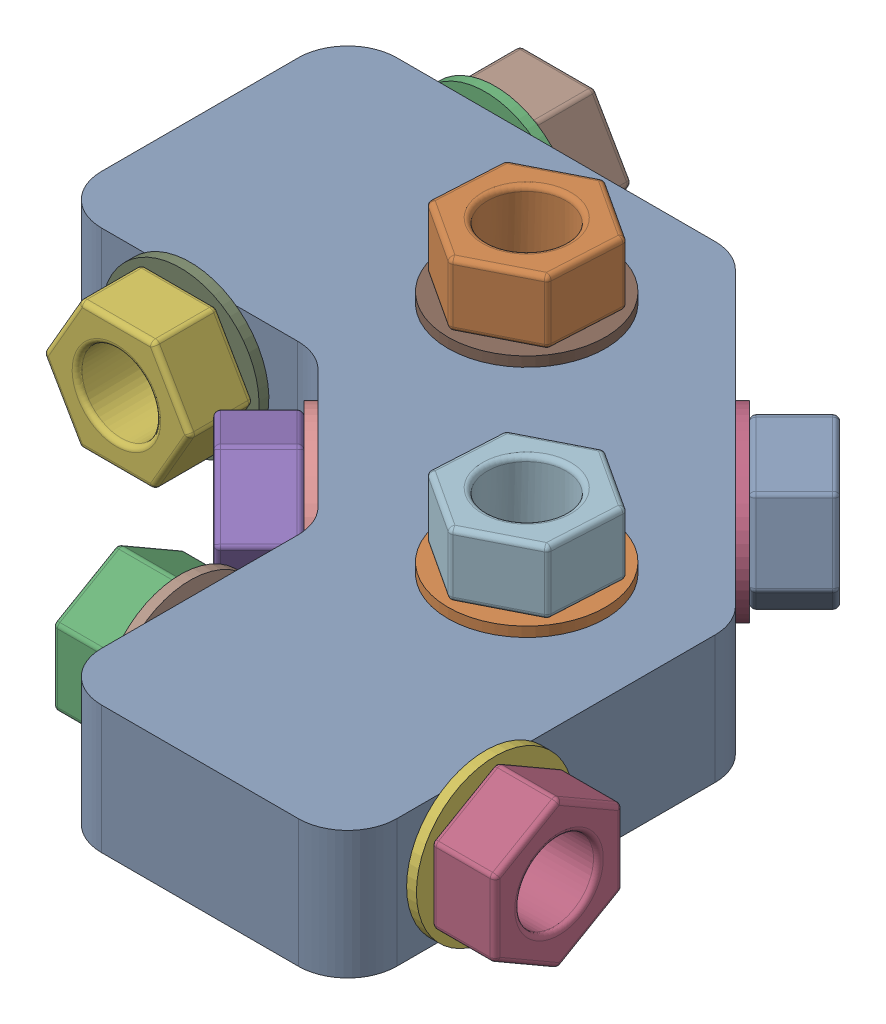
SolidWorks assembly Top Corner with Washers and Nuts, configuration Default. Lengths in mm.
Overall size (79.5 28 79.5).
21 component instances, 3 part files, 20 mates.
Components (placement in the parent):
- Corner (Upper)-1: Corner (Upper) [Default] at origin size (72 13 72)
- M8 Washer 16mm-1: M8 Washer 16mm [Default] at (15 13 8.7868) size (16 1 16)
- M8 Washer 16mm-2: M8 Washer 16mm [Default] at (-28 6.5 -31) x (1 0 0) z (0 -1 0) size (16 1 16)
- M8 Washer 16mm-3: M8 Washer 16mm [Default] at (14.4203 6.5 -14.4203) x (0.5 0.707107 0.5) z (0.5 -0.707107 0.5) size (16 1 16)
- M8 Washer 16mm-4: M8 Washer 16mm [Default] at (-8.7868 -1 -15) size (16 1 16)
- M8 Washer 16mm-5: M8 Washer 16mm [Default] at (31 6.5 28) x (0 1 0) z (0 0 1) size (16 1 16)
- M8 Washer 16mm-6: M8 Washer 16mm [Default] at (15 -1 8.7868) size (16 1 16)
- M8 Washer 16mm-7: M8 Washer 16mm [Default] at (-1 6.5 28) x (0 -1 0) z (0 0 1) size (16 1 16)
- M8 Washer 16mm-8: M8 Washer 16mm [Default] at (-28 6.5 0) x (1 0 0) z (0 -1 0) size (16 1 16)
- M8 Washer 16mm-9: M8 Washer 16mm [Default] at (-7.5 6.5 7.5) x (0.5 0.707107 0.5) z (0.5 -0.707107 0.5) size (16 1 16)
- M8 Washer 16mm-10: M8 Washer 16mm [Default] at (-8.7868 13 -15) size (16 1 16)
- M8 Nut-1: M8 Nut [Default] at (15 20.5 8.7868) x (-0.837169 0 -0.546944) z (-0.546944 0 0.837169) size (14.85 6.5 12.99)
- M8 Nut-2: M8 Nut [Default] at (19.0165 6.5 -19.0165) x (0.5 0.707107 0.5) z (0.5 -0.707107 0.5) size (14.85 6.5 12.99)
- M8 Nut-3: M8 Nut [Default] at (-8.7868 20.5 -15) x (-0.837169 0 -0.546944) z (-0.546944 0 0.837169) size (14.85 6.5 12.99)
- M8 Nut-4: M8 Nut [Default] at (-7.5 6.5 28) x (0 -1 0) z (0 0 1) size (14.85 6.5 12.99)
- M8 Nut-5: M8 Nut [Default] at (37.5 6.5 28) x (0 1 0) z (0 0 1) size (14.85 6.5 12.99)
- M8 Nut-6: M8 Nut [Default] at (-12.8033 6.5 12.8033) x (0.5 -0.707107 0.5) z (0.5 0.707107 0.5) size (14.85 6.5 12.99)
- M8 Nut-7: M8 Nut [Default] at (-28 6.5 7.5) x (1 0 0) z (0 1 0) size (14.85 6.5 12.99)
- M8 Nut-8: M8 Nut [Default] at (-8.7868 -7.5 -15) size (14.85 6.5 12.99)
- M8 Nut-9: M8 Nut [Default] at (-28 6.5 -37.5) x (1 0 0) z (0 -1 0) size (14.85 6.5 12.99)
- M8 Nut-10: M8 Nut [Default] at (15 -7.5 8.7868) size (14.85 6.5 12.99)
Mates (geometry in assembly coordinates):
- Coincident74: coincident aligned: circle of M8 Washer 16mm-10; circle of Corner (Upper)-1
- Coincident75: coincident aligned: circle of M8 Washer 16mm-1; circle of Corner (Upper)-1
- Coincident76: coincident aligned: circle of Corner (Upper)-1; circle of M8 Washer 16mm-9
- Coincident77: coincident aligned: circle of M8 Washer 16mm-8; circle of Corner (Upper)-1
- Coincident78: coincident anti-aligned: circle of Corner (Upper)-1; circle of M8 Washer 16mm-7
- Coincident79: coincident aligned: circle of M8 Washer 16mm-5; circle of Corner (Upper)-1
- Coincident80: coincident aligned: circle of M8 Washer 16mm-3; circle of Corner (Upper)-1
- Coincident81: coincident aligned: circle of Corner (Upper)-1; circle of M8 Washer 16mm-2
- Coincident82: coincident aligned: circle of Corner (Upper)-1; circle of M8 Washer 16mm-4
- Coincident83: coincident aligned: circle of Corner (Upper)-1; circle of M8 Washer 16mm-6
- Coincident85: coincident aligned: circle of M8 Nut-1; circle of M8 Washer 16mm-1
- Coincident88: coincident anti-aligned: circle of M8 Washer 16mm-2; circle of M8 Nut-9
- Coincident86: coincident anti-aligned: circle of M8 Washer 16mm-3; circle of M8 Nut-2
- Coincident93: coincident anti-aligned: circle of M8 Washer 16mm-4; circle of M8 Nut-8
- Coincident84: coincident anti-aligned: circle of M8 Washer 16mm-5; circle of M8 Nut-5
- Coincident92: coincident anti-aligned: circle of M8 Washer 16mm-6; circle of M8 Nut-10
- Coincident91: coincident anti-aligned: circle of M8 Washer 16mm-7; circle of M8 Nut-4
- Coincident90: coincident aligned: circle of M8 Nut-7; circle of M8 Washer 16mm-8
- Coincident89: coincident aligned: circle of M8 Nut-6; circle of M8 Washer 16mm-9
- Coincident87: coincident aligned: circle of M8 Nut-3; circle of M8 Washer 16mm-10
